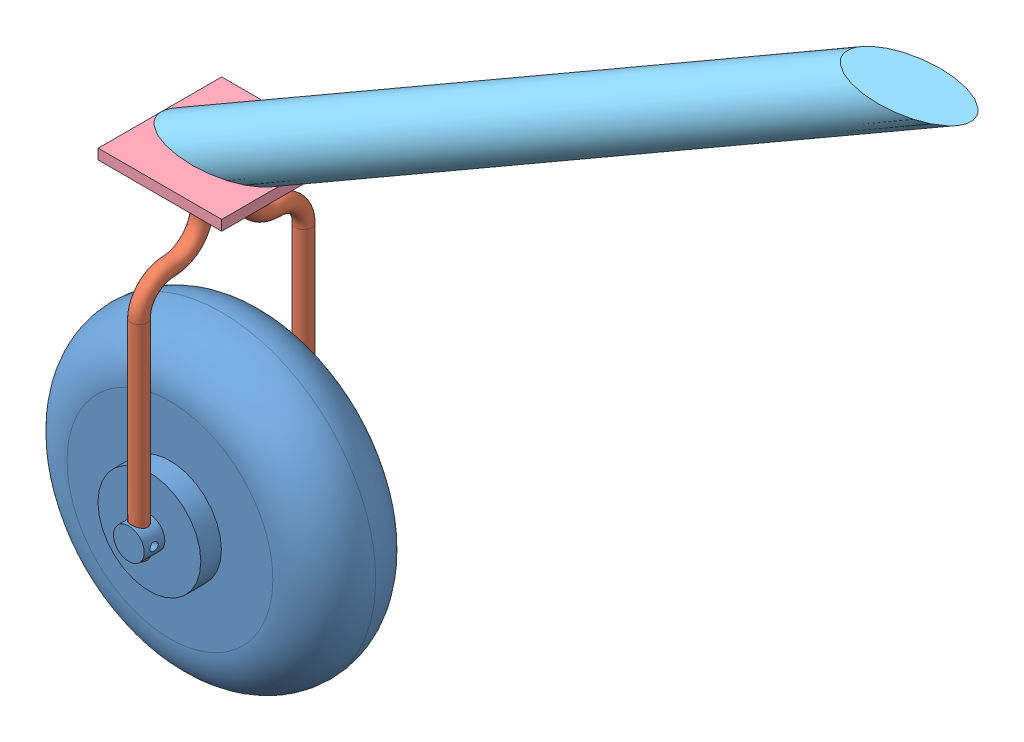
SolidWorks assembly Montaj2, configuration Varsayılan. Lengths in mm.
Overall size (219.34 205.85 45).
8 component instances, 5 part files, 3 mates.
Components (placement in the parent):
- inişteker-1: inişteker [Varsayılan] at (-69.7476 -84.3582 38.1266) x (0 0 -1) z (1 0 0) size (45 109.55 75)
  - teker-1: teker [Varsayılan] at (-96.4188 18.2391 16.1212) size (45 75 75)
  - tekertutacağı-1: tekertutacağı [Varsayılan] at (-95.165 -24.524 16.138) x (-0.00479 0 -0.999989) z (0.999989 0 -0.00479) size (4.12 72.8 19.37)
  - tekertutacağı-2: tekertutacağı [Varsayılan] at (-47.6741 -24.5106 16.0152) x (0.0286 0 0.999591) z (-0.999591 0 0.0286) size (4.12 72.8 19.37)
  - tekermenteşe-1: tekermenteşe [Varsayılan] at (-66.7729 80.5024 16.5594) x (0 0 1) z (-1 0 0) size (11.94 4.5 4.93)
  - tekermenteşe-2: tekermenteşe [Varsayılan] at (-76.0587 80.5345 16.0473) x (0 0 -1) z (1 0 0) size (11.94 4.5 4.93)
  - sapbağlantı-2: sapbağlantı [Varsayılan] at (-71.4165 76.9961 16.185) x (0 0 -1) z (1 0 0) size (30 7.5 30)
- Parça1-1: Parça1 [Varsayılan] at (-16.5332 35.0589 109.2187) size (196.8 96.3 15)
Mates (geometry in assembly coordinates):
- Paralel1: parallel: plane of inişteker-1/sapbağlantı-2 through (-53.5626 5.9264 109.5431) normal (0 1 0); plane of Parça1-1 through (-38.5801 5.9264 92.2186) normal (0 -1 0)
- Çakışık2: coincident: plane of inişteker-1/sapbağlantı-2 through (-53.5626 5.9264 109.5431) normal (0 1 0); plane of Parça1-1 through (-38.5801 5.9264 92.2186) normal (0 -1 0)
- Kilitle1: lock: unknown of inişteker-1/sapbağlantı-2; unknown of Parça1-1
